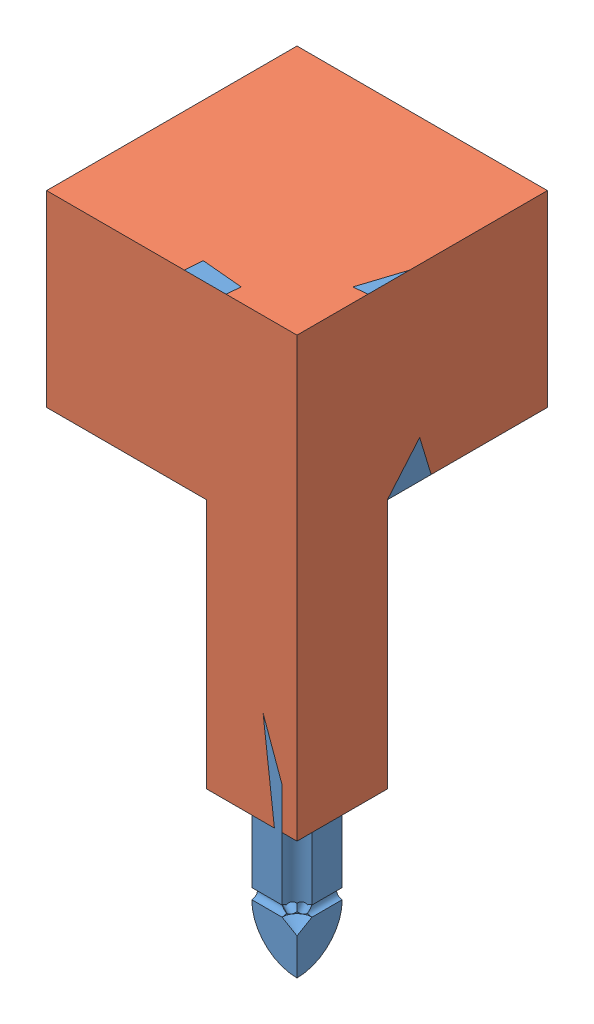
SolidWorks assembly Assem1, configuration Default. Lengths in mm.
Overall size (25.43 56.47 25.43).
2 component instances, 2 part files, 3 mates.
Components (placement in the parent):
- Part_Pintle_V2.2-1: Part_Pintle_V2.2 [Default] at (16.2061 22.3053 50.7862) size (17.81 56.47 17.81)
- PintleV2_.2-1: PintleV2_.2 [Default] at (16.2061 70.7841 50.7862) x (-1 0 0) z (0 0 1) size (25.4 44.45 25.4)
Mates (geometry in assembly coordinates):
- Coincident2: coincident: plane of Part_Pintle_V2.2-1 through (16.2061 70.7841 50.7862) normal (0 1 0); plane of PintleV2_.2-1 through (16.2061 70.7841 50.7862) normal (0 1 0)
- Coincident3: coincident: plane of Part_Pintle_V2.2-1 through (16.2061 14.3122 50.7862) normal (1 0 0); plane of PintleV2_.2-1 through (16.2061 51.7341 50.7862) normal (1 0 0)
- Coincident4: coincident: plane of Part_Pintle_V2.2-1 through (-14.2433 14.3122 50.7862) normal (0 0 1); plane of PintleV2_.2-1 through (16.2061 51.7341 50.7862) normal (0 0 1)
